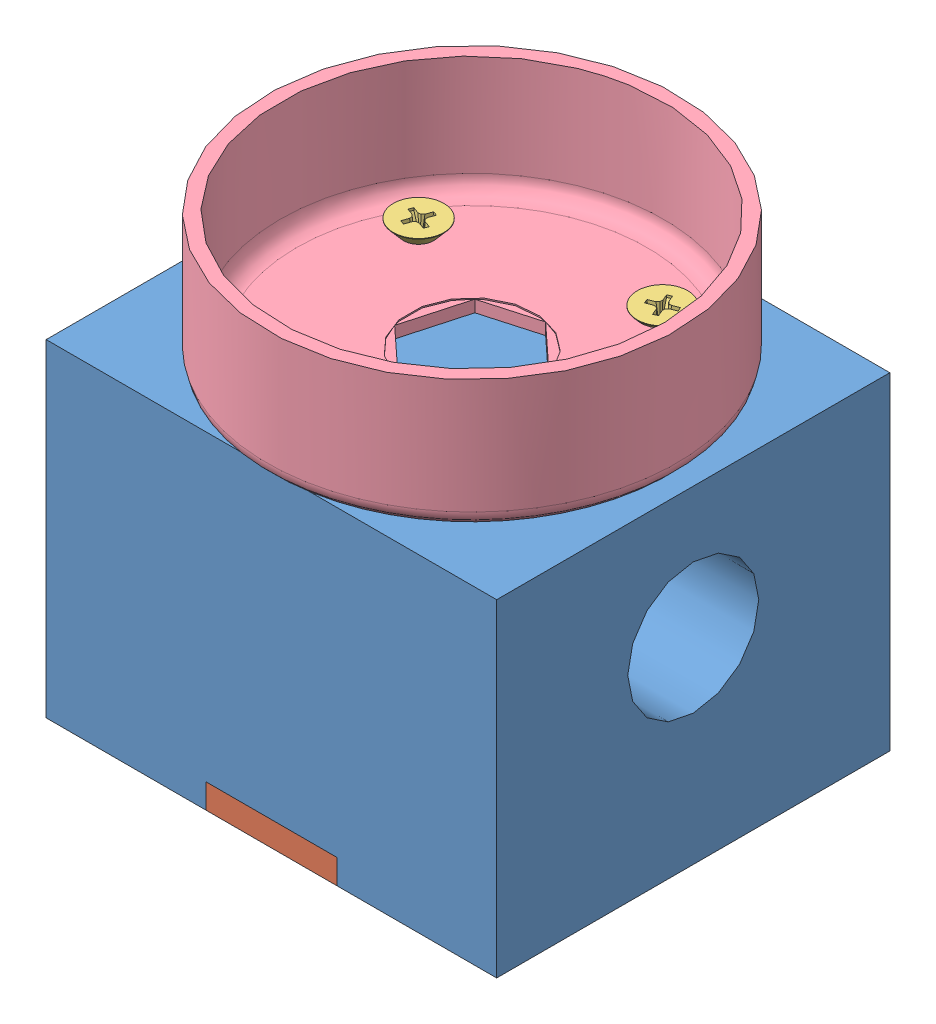
SolidWorks assembly INTERIOR BLOCK SUB ASSEMBLY, configuration Default. Lengths in mm.
Overall size (98.03 89.64 98.03).
10 component instances, 4 part files, 12 mates.
Components (placement in the parent):
- INTERIOR BLOCK TERM PROJECT-1: INTERIOR BLOCK TERM PROJECT [Default] at origin size (87.31 63.5 76.2)
- BLOCK SUPPORT-1: BLOCK SUPPORT [Default] at origin size (25.4 4.76 76.2)
- 90031A247_Phillips Flat Head Screws for Wood-1: 90031A247_Phillips Flat Head Screws for Wood [90031A247] at (0 11.9622 -25.4) x (0 1 0) z (0.208565 0 0.978008) size (25.4 9.78 9.78)
- 90031A247_Phillips Flat Head Screws for Wood-2: 90031A247_Phillips Flat Head Screws for Wood [90031A247] at (0 12.1628 0) x (0 1 0) z (0.620381 0 0.7843) size (25.4 9.78 9.78)
- 90031A247_Phillips Flat Head Screws for Wood-3: 90031A247_Phillips Flat Head Screws for Wood [90031A247] at (0 12.0573 25.4) x (0 1 0) z (0.51763 0 0.855605) size (25.4 9.78 9.78)
- BLOCK FILTER-1: BLOCK FILTER [Default] at (1.6736 63.5 0.916) x (-0.962005 0 0.273032) z (-0.273032 0 -0.962005) size (79.38 25.4 79.38)
- 90031A247_Phillips Flat Head Screws for Wood-4: 90031A247_Phillips Flat Head Screws for Wood [90031A247] at (13.7574 54.2448 -23.947) x (0 -1 0) z (0.380339 0 0.924847) size (25.4 9.78 9.78)
- 90031A247_Phillips Flat Head Screws for Wood-5: 90031A247_Phillips Flat Head Screws for Wood [90031A247] at (-12.7623 55.3403 22.816) x (0 -1 0) z (-0.061609 0 0.9981) size (25.4 9.78 9.78)
- 90031A247_Phillips Flat Head Screws for Wood-6: 90031A247_Phillips Flat Head Screws for Wood [90031A247] at (25.0167 55.6093 15.7242) x (0 -1 0) z (-0.006381 0 0.99998) size (25.4 9.78 9.78)
- 90031A247_Phillips Flat Head Screws for Wood-7: 90031A247_Phillips Flat Head Screws for Wood [90031A247] at (-23.068 55.7143 -13.4954) x (0 -1 0) z (-0.34043 0 0.94027) size (25.4 9.78 9.78)
Mates (geometry in assembly coordinates):
- Coincident1: coincident anti-aligned: plane of INTERIOR BLOCK TERM PROJECT-1 through (0 4.7625 0) normal (0 -1 0); plane of BLOCK SUPPORT-1 through (0 4.7625 0) normal (0 1 0)
- Parallel1: parallel anti-aligned: line of INTERIOR BLOCK TERM PROJECT-1 through (-12.7 4.7625 -38.1) axis (1 0 0); line of BLOCK SUPPORT-1 through (12.7 0 -38.1) axis (-1 0 0)
- Coincident3: coincident aligned: line of INTERIOR BLOCK TERM PROJECT-1 through (43.6562 0 -38.1) axis (-1 0 0); line of BLOCK SUPPORT-1 through (12.7 0 -38.1) axis (-1 0 0)
- Concentric1: concentric anti-aligned: circle of BLOCK SUPPORT-1; circle of 90031A247_Phillips Flat Head Screws for Wood-1
- Coincident4: coincident anti-aligned: plane of INTERIOR BLOCK TERM PROJECT-1 through (-12.7 4.7625 38.1) normal (1 0 0); plane of BLOCK SUPPORT-1 through (-12.7 4.7625 -38.1) normal (-1 0 0)
- Concentric2: concentric anti-aligned: circle of BLOCK SUPPORT-1; circle of 90031A247_Phillips Flat Head Screws for Wood-2
- Concentric3: concentric anti-aligned: circle of BLOCK SUPPORT-1; circle of 90031A247_Phillips Flat Head Screws for Wood-3
- Coincident5: coincident anti-aligned: plane of INTERIOR BLOCK TERM PROJECT-1 through (0 63.5 0) normal (0 1 0); circle of BLOCK FILTER-1
- Concentric5: concentric aligned: circle of BLOCK FILTER-1; circle of 90031A247_Phillips Flat Head Screws for Wood-6
- Concentric8: concentric aligned: circle of BLOCK FILTER-1; circle of 90031A247_Phillips Flat Head Screws for Wood-5
- Concentric9: concentric aligned: circle of BLOCK FILTER-1; circle of 90031A247_Phillips Flat Head Screws for Wood-7
- Concentric10: concentric aligned: circle of BLOCK FILTER-1; circle of 90031A247_Phillips Flat Head Screws for Wood-4
